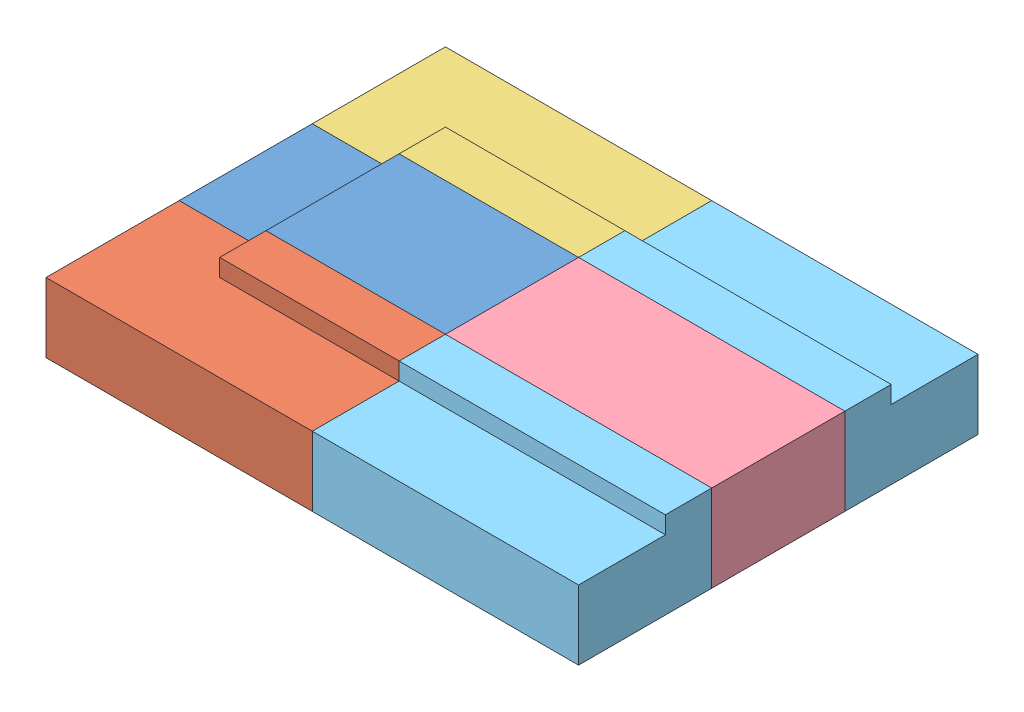
SolidWorks assembly Heat Treat Asm Top-Bot Alt, configuration Default. Lengths in mm.
Overall size (460 75 345).
6 component instances, 5 part files, 12 mates.
Components (placement in the parent):
- Brick-Sharp-BackCut-1: Brick-Sharp-BackCut [Default] at (64.2972 119.1646 188.5049) size (230 75 115)
- Brick-Sharp-BackLeftCut-1: Brick-Sharp-BackLeftCut [Default] at (64.2972 119.1646 303.5049) size (230 75 115)
- Brick-Sharp-BackRightCut-1: Brick-Sharp-BackRightCut [Default] at (64.2972 119.1646 73.5049) size (230 75 115)
- Brick-Sharp-2: Brick-Sharp [Default] at (294.2972 119.1646 188.5049) size (230 75 115)
- Brick-Sharp-SideCut-1: Brick-Sharp-SideCut [Default] at (294.2972 119.1646 73.5049) size (230 75 115)
- Brick-Sharp-SideCut-2: Brick-Sharp-SideCut [Default] at (294.2972 119.1646 303.5049) x (-1 0 0) z (0 0 -1) size (230 75 115)
Mates (geometry in assembly coordinates):
- Coincident38: coincident: plane of Brick-Sharp-BackCut-1 through (-50.7028 156.6646 246.0049) normal (0 0 1); plane of Brick-Sharp-BackLeftCut-1 through (-50.7028 156.6646 246.0049) normal (0 0 -1)
- Coincident40: coincident aligned: line of Brick-Sharp-BackCut-1 through (179.2972 156.6646 246.0049) axis (0 0 -1); line of Brick-Sharp-BackLeftCut-1 through (179.2972 156.6646 286.0049) axis (0 0 -1)
- Coincident41: coincident: plane of Brick-Sharp-BackCut-1 through (-50.7028 156.6646 131.0049) normal (0 0 -1); plane of Brick-Sharp-BackRightCut-1 through (-50.7028 156.6646 131.0049) normal (0 0 1)
- Coincident42: coincident aligned: line of Brick-Sharp-BackCut-1 through (179.2972 156.6646 246.0049) axis (0 0 -1); line of Brick-Sharp-BackRightCut-1 through (179.2972 156.6646 131.0049) axis (0 0 -1)
- Coincident43: coincident anti-aligned: plane of Brick-Sharp-BackLeftCut-1 through (179.2972 156.6646 246.0049) normal (1 0 0); plane of Brick-Sharp-SideCut-2 through (179.2972 156.6646 361.0049) normal (-1 0 0)
- Coincident44: coincident aligned: line of Brick-Sharp-BackLeftCut-1 through (179.2972 141.6646 361.0049) axis (0 -1 0); line of Brick-Sharp-SideCut-2 through (179.2972 141.6646 361.0049) axis (0 -1 0)
- Coincident45: coincident anti-aligned: line of Brick-Sharp-BackLeftCut-1 through (179.2972 81.6646 361.0049) axis (0 0 -1); line of Brick-Sharp-SideCut-2 through (179.2972 81.6646 246.0049) axis (0 0 1)
- Coincident46: coincident anti-aligned: plane of Brick-Sharp-2 through (179.2972 156.6646 246.0049) normal (0 0 1); plane of Brick-Sharp-SideCut-2 through (409.2972 156.6646 246.0049) normal (0 0 -1)
- Coincident47: coincident anti-aligned: plane of Brick-Sharp-BackCut-1 through (179.2972 156.6646 131.0049) normal (1 0 0); plane of Brick-Sharp-2 through (179.2972 156.6646 131.0049) normal (-1 0 0)
- Coincident48: coincident anti-aligned: line of Brick-Sharp-BackCut-1 through (179.2972 156.6646 246.0049) axis (0 0 -1); line of Brick-Sharp-2 through (179.2972 156.6646 131.0049) axis (0 0 1)
- Coincident49: coincident: line of Brick-Sharp-2 through (409.2972 156.6646 131.0049) axis (0 -1 0); line of Brick-Sharp-SideCut-1 through (409.2972 156.6646 131.0049) axis (0 -1 0)
- Coincident50: coincident anti-aligned: line of Brick-Sharp-2 through (409.2972 156.6646 131.0049) axis (-1 0 0); line of Brick-Sharp-SideCut-1 through (179.2972 156.6646 131.0049) axis (1 0 0)
